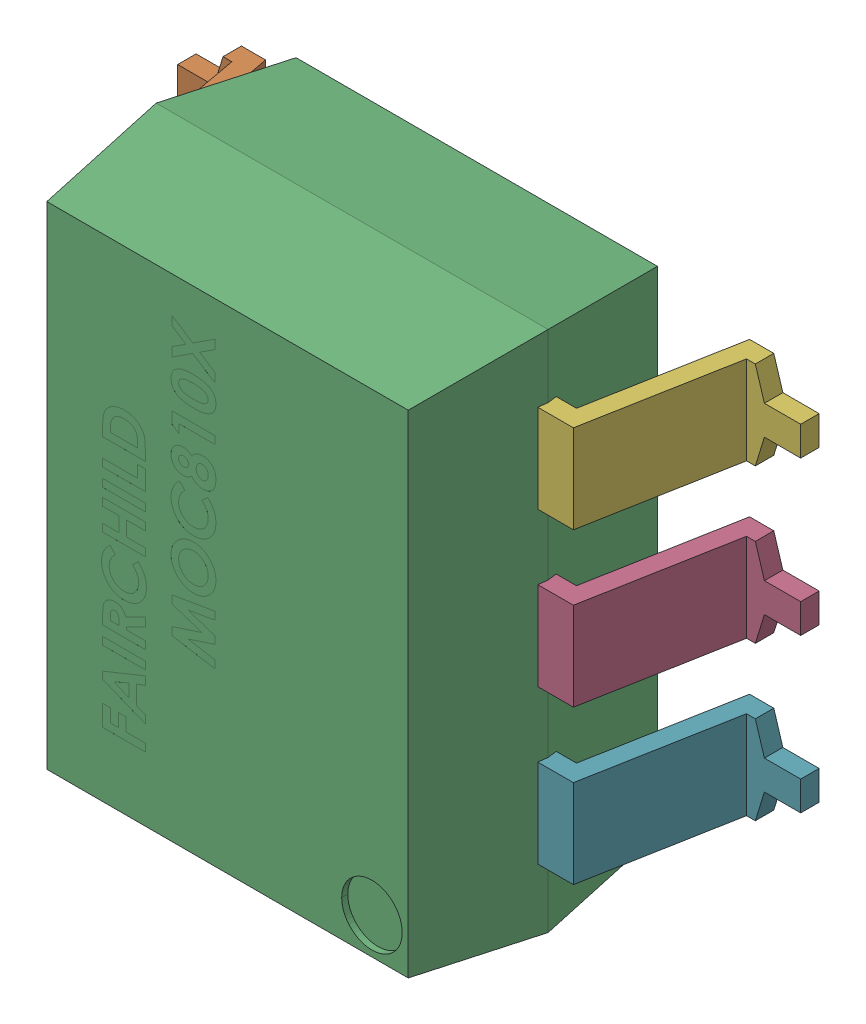
SolidWorks assembly U6_1.step, configuration Default. Lengths in mm.
Overall size (10.3 8.64 4.63).
8 component instances, 2 part files, 0 mates.
Components (placement in the parent):
- SMD DIP-6_1.step-3: SMD DIP-6_1.step [Default] at (401.3199 313.1819 2.5654) x (0 1 0) z (1 0 0) size (8.63 4.63 10.3)
  - MOC810X_SOIC6_PIN_1.step-16: MOC810X_SOIC6_PIN_1.step [Default] at (2.5236 0.1223 -5.1276) x (-1 0 0) z (0 0 -1) size (1.46 2.72 2.11)
  - MOC810X_SOIC6_PIN_1.step-17: MOC810X_SOIC6_PIN_1.step [Default] at (5.0636 0.1223 -5.1276) x (-1 0 0) z (0 0 -1) size (1.46 2.72 2.11)
  - MOC810X_SOIC6_BODY_1.step-3: MOC810X_SOIC6_BODY_1.step [Default] at (-2.5239 -0.0302 1.3524) size (8.63 4.12 6.48)
  - MOC810X_SOIC6_PIN_1.step-18: MOC810X_SOIC6_PIN_1.step [Default] at (1.0636 0.1223 1.3524) size (1.46 2.72 2.11)
  - MOC810X_SOIC6_PIN_1.step-19: MOC810X_SOIC6_PIN_1.step [Default] at (-0.0164 0.1223 -5.1276) x (-1 0 0) z (0 0 -1) size (1.46 2.72 2.11)
  - MOC810X_SOIC6_PIN_1.step-20: MOC810X_SOIC6_PIN_1.step [Default] at (3.6036 0.1223 1.3524) size (1.46 2.72 2.11)
  - MOC810X_SOIC6_PIN_1.step-21: MOC810X_SOIC6_PIN_1.step [Default] at (-1.4764 0.1223 1.3524) size (1.46 2.72 2.11)
